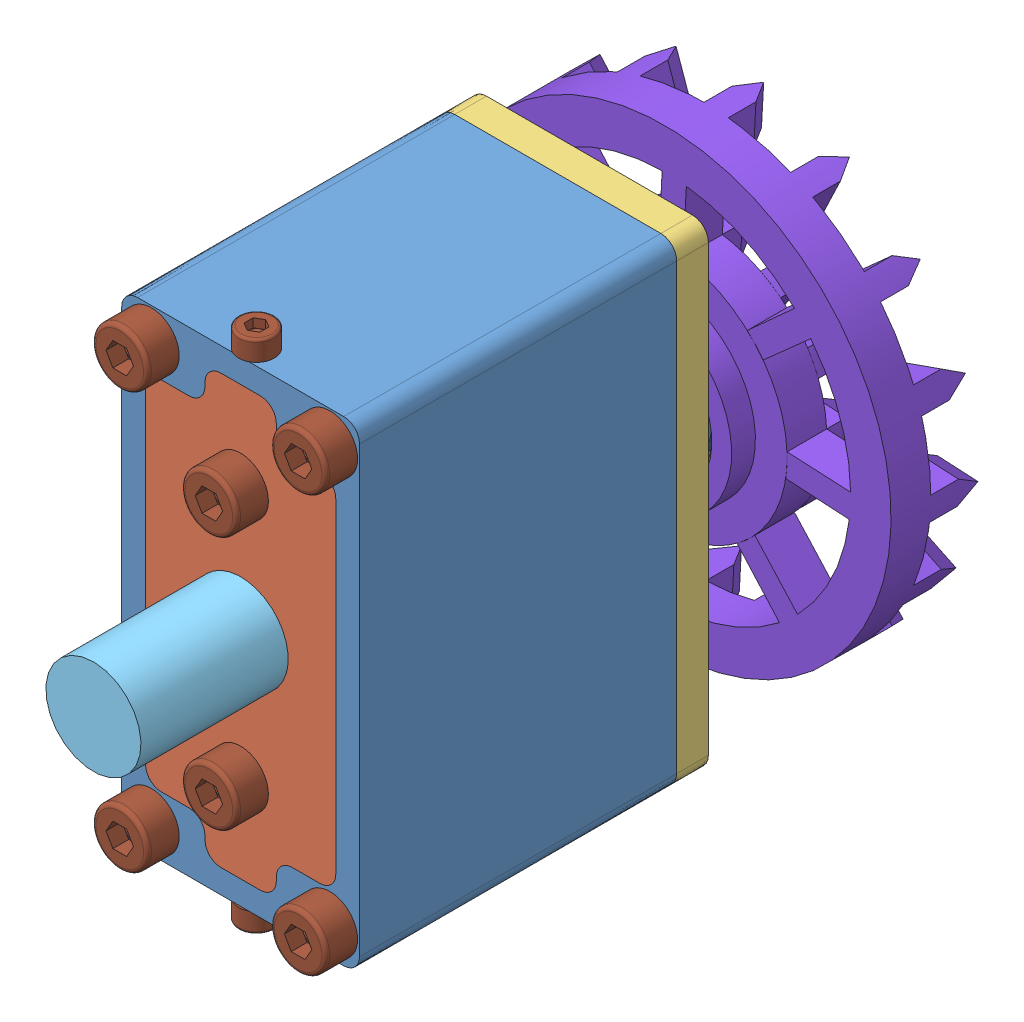
SolidWorks assembly 电磁铁, configuration 默认. Lengths in mm.
Overall size (60.2 65 83).
20 component instances, 12 part files, 41 mates.
Components (placement in the parent):
- 磁铁盒03-1: 磁铁盒03 [默认] at (53.6549 -3.2014 -15) size (30 60 40)
- 磁铁盒01-1: 磁铁盒01 [默认] at (53.6549 -3.2014 21) size (24 54 4)
- 磁铁盒02-1: 磁铁盒02 [默认] at (53.6549 -3.2014 -19) size (30 60 4)
- 电磁铁和芯01-1: 电磁铁和芯01 [默认] at (53.6549 12.7986 5) x (1 0 0) z (0 -1 0) size (14.6 18 14.6)
- 电磁铁和芯01-3: 电磁铁和芯01 [默认] at (53.6549 -19.2014 5) x (1 0 0) z (0 -1 0) size (14.6 18 14.6)
- 芯-1: 芯 [默认] at (53.6549 -3.2014 33.5683) x (0.571928 -0.820304 0) z (0 0 -1) size (12 12 80)
- 弹簧-1: 弹簧 [默认] at (53.6549 -3.2014 21) x (-0.978432 0.206569 0) z (-0.206569 -0.978432 0) size (15 26 17.32)
- 衔铁03-1: 衔铁03 [默认] at (53.6549 -3.2014 -3.9303) x (0 -1 0) z (0 0 1) size (37.5 16.5 3)
- 电磁铁锁紧大-1: 电磁铁锁紧大 [默认] at (53.6549 -3.2014 -33.4317) x (-0.053634 -0.998561 0) z (0 0 -1) size (57.22 57.22 14)
- circlips for holes--type a gb-2: circlips for holes--type a gb [GB_CONNECTING_PIECE_RING_RRH 18] at (53.6549 -2.7014 -26.4317) size (19.5 18.76 1)
- deep groove ball bearings gb-7: deep groove ball bearings gb [Rolling bearings 61801 GB 276-94] at (53.6549 -3.2014 -29.4317) x (0 0 -1) z (1 0 0) size (4 18 18)
- hexagon socket head cap screws gb-6: hexagon socket head cap screws gb [GB_FASTENER_SCREWS_HSHCS M2.5X10-N] at (53.6549 29.2986 23) x (0 -1 0) z (0 0 1) size (12.5 4.5 4.5)
- hexagon socket head cap screws gb-7: hexagon socket head cap screws gb [GB_FASTENER_SCREWS_HSHCS M2.5X10-N] at (53.6549 -35.7014 23) x (0 1 0) z (0 0 1) size (12.5 4.5 4.5)
- hexagon socket head cap screws gb-9: hexagon socket head cap screws gb [GB_FASTENER_SCREWS_HSHCS M4X10-N] at (53.6549 12.7986 29) x (0 0 -1) z (1 0 0) size (14 7 7)
- hexagon socket head cap screws gb-10: hexagon socket head cap screws gb [GB_FASTENER_SCREWS_HSHCS M4X10-N] at (53.6549 -19.2014 29) x (0 0 -1) z (1 0 0) size (14 7 7)
- hexagon socket head cap screws gb-17: hexagon socket head cap screws gb [GB_FASTENER_SCREWS_HSHCS M4X10-N] at (42.4049 -29.4514 29) x (0 0 -1) z (1 0 0) size (14 7 7)
- hexagon socket head cap screws gb-18: hexagon socket head cap screws gb [GB_FASTENER_SCREWS_HSHCS M4X10-N] at (64.9049 -29.4514 29) x (0 0 -1) z (1 0 0) size (14 7 7)
- hexagon socket head cap screws gb-19: hexagon socket head cap screws gb [GB_FASTENER_SCREWS_HSHCS M4X10-N] at (64.9049 23.0486 29) x (0 0 -1) z (1 0 0) size (14 7 7)
- hexagon socket head cap screws gb-20: hexagon socket head cap screws gb [GB_FASTENER_SCREWS_HSHCS M4X10-N] at (42.4049 23.0486 29) x (0 0 -1) z (1 0 0) size (14 7 7)
- circlips for shaft--type a large gb-1: circlips for shaft--type a large gb [GB_CONNECTING_PIECE_RING_RRA 12] at (53.6549 -2.7714 -31.4317) size (13.6 15.97 1)
Mates (geometry in assembly coordinates):
- 重合1: coincident aligned: plane of 磁铁盒03-1 through (53.6549 -3.2014 25) normal (0 0 1); plane of 磁铁盒01-1 through (51.1549 -28.2014 25) normal (0 0 1)
- 同心1: concentric aligned: cylinder of 磁铁盒03-1 through (53.6549 26.7986 23) axis (0 1 0) radius 1.025; cylinder of 磁铁盒01-1 through (53.6549 23.7986 23) axis (0 1 0) radius 1.025
- 重合2: coincident anti-aligned: plane of 磁铁盒03-1 through (53.6549 23.7986 25) normal (0 -1 0); plane of 磁铁盒01-1 through (56.1549 23.7986 25) normal (0 1 0)
- 同心2: concentric anti-aligned: cylinder of 磁铁盒03-1 through (42.4049 23.0486 -15) axis (0 0 -1) radius 1.65; cylinder of 磁铁盒02-1 through (42.4049 23.0486 -15) axis (0 0 1) radius 1.65
- 同心3: concentric anti-aligned: cylinder of 磁铁盒03-1 through (64.9049 23.0486 -15) axis (0 0 -1) radius 1.65; cylinder of 磁铁盒02-1 through (64.9049 23.0486 -15) axis (0 0 1) radius 1.65
- 重合4: coincident anti-aligned: plane of 磁铁盒03-1 through (53.6549 -3.2014 -15) normal (0 0 -1); plane of 磁铁盒02-1 through (53.6549 -3.2014 -15) normal (0 0 1)
- 同心4: concentric anti-aligned: cylinder of 电磁铁和芯01-1 through (53.6549 12.7986 21) axis (0 0 1) radius 1.65; cylinder of 磁铁盒01-1 through (53.6549 12.7986 21) axis (0 0 -1) radius 1.65
- 重合6: coincident anti-aligned: plane of 磁铁盒01-1 through (51.1549 -28.2014 21) normal (0 0 -1); plane of 电磁铁和芯01-1 through (53.6549 12.7986 21) normal (0 0 1)
- 同心5: concentric anti-aligned: cylinder of 电磁铁和芯01-3 through (53.6549 -19.2014 21) axis (0 0 1) radius 1.65; cylinder of 磁铁盒01-1 through (53.6549 -19.2014 21) axis (0 0 -1) radius 1.65
- 重合7: coincident anti-aligned: plane of 磁铁盒01-1 through (51.1549 -28.2014 21) normal (0 0 -1); plane of 电磁铁和芯01-3 through (53.6549 -19.2014 21) normal (0 0 1)
- 同心6: concentric anti-aligned: cylinder of 磁铁盒01-1 through (53.6549 -3.2014 25) axis (0 0 -1) radius 6; cylinder of 芯-1 through (53.6549 -3.2014 43.5683) axis (0 0 1) radius 6
- 同心8: concentric aligned: cylinder of 芯-1 through (53.6549 -3.2014 43.5683) axis (0 0 1) radius 6; line of 弹簧-1 through (53.6549 -3.2014 -1.4758) axis (0 0 1)
- 同心9: concentric anti-aligned: cylinder of 芯-1 through (53.6549 -3.2014 43.5683) axis (0 0 1) radius 6; cylinder of 衔铁03-1 through (53.6549 -3.2014 -0.9303) axis (0 0 -1) radius 6
- 平行1: parallel aligned: plane of 磁铁盒03-1 through (38.6549 -3.2014 25) normal (-1 0 0); plane of 衔铁03-1 through (45.4049 -21.9514 -0.9303) normal (-1 0 0)
- 同心10: concentric anti-aligned: cylinder of 芯-1 through (53.6549 -3.2014 43.5683) axis (0 0 1) radius 6; cylinder of 电磁铁锁紧大-1 through (53.6549 -3.2014 -25.4317) axis (0 0 -1) radius 9
- 同心131: concentric anti-aligned: cylinder of 电磁铁锁紧大-1 through (53.6549 -3.2014 -25.4317) axis (0 0 -1) radius 9; cylinder of deep groove ball bearings gb-7 through (53.6549 -3.2014 -22.4603) axis (0 0 1) radius 6
- 重合221: coincident anti-aligned: plane of circlips for holes--type a gb-2 through (53.6549 -2.7014 -27.4317) normal (0 0 -1); plane of deep groove ball bearings gb-7 through (53.6549 3.7986 -27.4317) normal (0 0 1)
- 同心141: concentric aligned: cylinder of circlips for holes--type a gb-2 through (53.6549 -3.2014 -27.4317) axis (0 0 1) radius 8.15; cylinder of deep groove ball bearings gb-7 through (53.6549 -3.2014 -22.4603) axis (0 0 1) radius 6
- 重合241: coincident anti-aligned: plane of 电磁铁锁紧大-1 through (43.9189 -2.6784 -26.4317) normal (0 0 -1); plane of circlips for holes--type a gb-2 through (53.6549 -2.7014 -26.4317) normal (0 0 1)
- 同心151: concentric aligned: cylinder of 芯-1 through (53.6549 -3.2014 43.5683) axis (0 0 1) radius 6; cylinder of deep groove ball bearings gb-7 through (53.6549 -3.2014 -22.4603) axis (0 0 1) radius 6
- 重合251: coincident aligned: plane of 芯-1 through (48.733 -6.6329 -31.4317) normal (0 0 -1); plane of deep groove ball bearings gb-7 through (53.6549 5.7986 -31.4317) normal (0 0 -1)
- 同心18: concentric aligned: cylinder of 磁铁盒03-1 through (53.6549 26.7986 23) axis (0 1 0) radius 1.025; cylinder of hexagon socket head cap screws gb-6 through (53.6549 16.7986 23) axis (0 1 0) radius 1.25
- 重合28: coincident anti-aligned: plane of 磁铁盒03-1 through (53.6549 26.7986 25) normal (0 1 0); plane of hexagon socket head cap screws gb-6 through (53.6549 26.7986 23) normal (0 -1 0)
- 同心19: concentric anti-aligned: cylinder of 磁铁盒03-1 through (53.6549 26.7986 23) axis (0 1 0) radius 1.025; cylinder of hexagon socket head cap screws gb-7 through (53.6549 -23.2014 23) axis (0 -1 0) radius 1.25
- 重合29: coincident anti-aligned: plane of 磁铁盒03-1 through (53.6549 -33.2014 25) normal (0 -1 0); plane of hexagon socket head cap screws gb-7 through (53.6549 -33.2014 23) normal (0 1 0)
- 同心20: concentric anti-aligned: cylinder of 磁铁盒01-1 through (53.6549 12.7986 21) axis (0 0 -1) radius 1.65; cylinder of hexagon socket head cap screws gb-9 through (53.6549 12.7986 15) axis (0 0 1) radius 2
- 重合30: coincident anti-aligned: plane of 磁铁盒01-1 through (51.1549 -28.2014 25) normal (0 0 1); plane of hexagon socket head cap screws gb-9 through (53.6549 12.7986 25) normal (0 0 -1)
- 同心21: concentric anti-aligned: cylinder of 磁铁盒01-1 through (53.6549 -19.2014 21) axis (0 0 -1) radius 1.65; cylinder of hexagon socket head cap screws gb-10 through (53.6549 -19.2014 15) axis (0 0 1) radius 2
- 重合31: coincident anti-aligned: plane of 磁铁盒01-1 through (51.1549 -28.2014 25) normal (0 0 1); plane of hexagon socket head cap screws gb-10 through (53.6549 -19.2014 25) normal (0 0 -1)
- 同心26: concentric aligned: cylinder of 磁铁盒03-1 through (42.4049 -29.4514 25) axis (0 0 1) radius 1.65; cylinder of hexagon socket head cap screws gb-17 through (42.4049 -29.4514 15) axis (0 0 1) radius 2
- 重合36: coincident anti-aligned: plane of 磁铁盒03-1 through (53.6549 -3.2014 25) normal (0 0 1); plane of hexagon socket head cap screws gb-17 through (42.4049 -29.4514 25) normal (0 0 -1)
- 同心27: concentric aligned: cylinder of 磁铁盒03-1 through (64.9049 -29.4514 25) axis (0 0 1) radius 1.65; cylinder of hexagon socket head cap screws gb-18 through (64.9049 -29.4514 15) axis (0 0 1) radius 2
- 重合37: coincident anti-aligned: plane of 磁铁盒03-1 through (53.6549 -3.2014 25) normal (0 0 1); plane of hexagon socket head cap screws gb-18 through (64.9049 -29.4514 25) normal (0 0 -1)
- 同心28: concentric aligned: cylinder of 磁铁盒03-1 through (64.9049 23.0486 25) axis (0 0 1) radius 1.65; cylinder of hexagon socket head cap screws gb-19 through (64.9049 23.0486 15) axis (0 0 1) radius 2
- 重合38: coincident anti-aligned: plane of 磁铁盒03-1 through (53.6549 -3.2014 25) normal (0 0 1); plane of hexagon socket head cap screws gb-19 through (64.9049 23.0486 25) normal (0 0 -1)
- 同心29: concentric aligned: cylinder of 磁铁盒03-1 through (42.4049 23.0486 25) axis (0 0 1) radius 1.65; cylinder of hexagon socket head cap screws gb-20 through (42.4049 23.0486 15) axis (0 0 1) radius 2
- 重合39: coincident anti-aligned: plane of 磁铁盒03-1 through (53.6549 -3.2014 25) normal (0 0 1); plane of hexagon socket head cap screws gb-20 through (42.4049 23.0486 25) normal (0 0 -1)
- 锁定1: lock: unknown of 芯-1; unknown of 衔铁03-1
- 重合252: coincident: plane of 磁铁盒01-1 through (51.1549 -28.2014 21) normal (0 0 -1); point of 弹簧-1
- 同心1521: concentric anti-aligned: cylinder of 芯-1 through (53.6549 -3.2014 43.5683) axis (0 0 -1) radius 6; cylinder of circlips for shaft--type a large gb-1 through (53.6549 -3.2014 -32.4317) axis (0 0 1) radius 5.5
- 重合2531: coincident anti-aligned: plane of 芯-1 through (48.733 -6.6329 -31.4317) normal (0 0 -1); plane of circlips for shaft--type a large gb-1 through (53.6549 -3.2014 -31.4317) normal (0 0 1)
